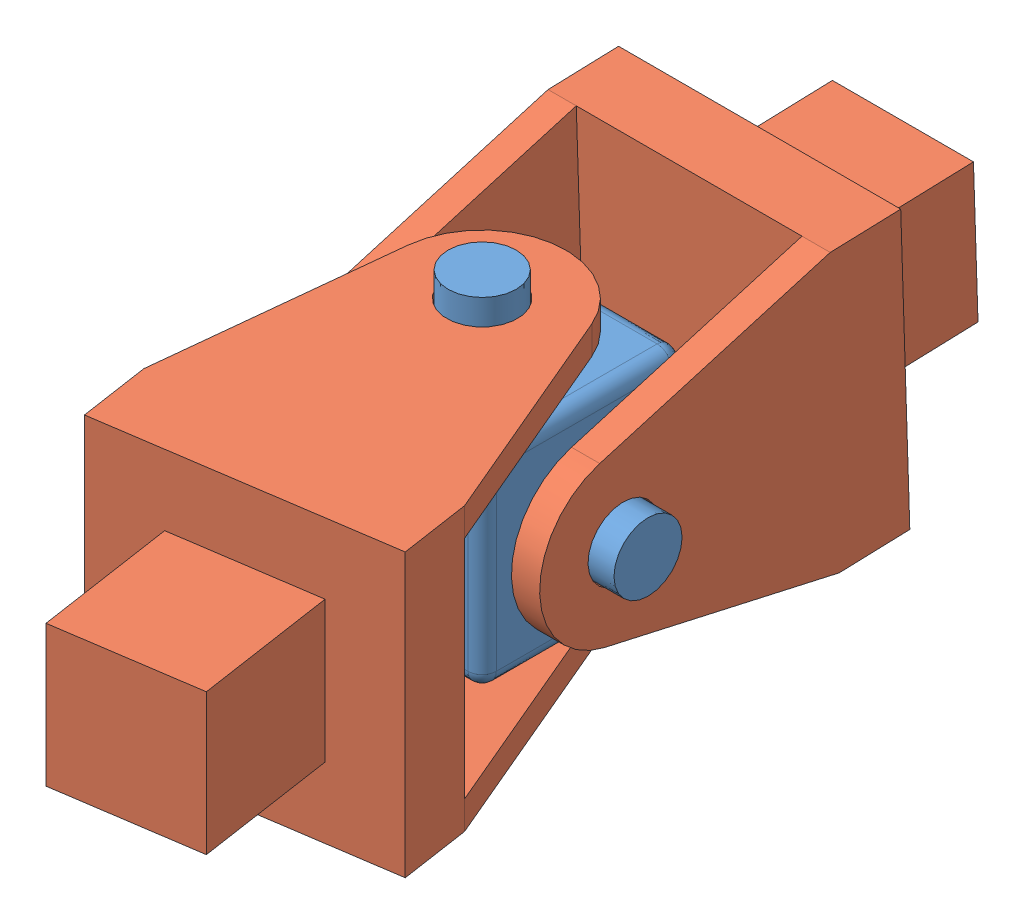
SolidWorks assembly U_assy, configuration Default. Lengths in mm.
Overall size (26.08 23.51 61.46).
3 component instances, 2 part files, 4 mates.
Components (placement in the parent):
- connector_new-2: connector_new [Default] at (0.0881 -0.2538 3.7177) size (23.51 23.51 14.4)
- U_leg-3: U_leg [Default] at (0.0881 0.3908 -16.2719) x (0 0.99948 0.032232) z (1 0 0) size (20 35.93 20)
- U_leg-4: U_leg [Default] at (3.0454 -0.2538 23.4979) x (0.989007 0 -0.147868) z (0 1 0) size (20 35.93 20)
Mates (geometry in assembly coordinates):
- Coincident3: coincident aligned: plane of connector_new-2 through (0.0881 -0.2538 3.7177) normal (1 0 0); plane of U_leg-3 through (0.0881 0.3908 -16.2719) normal (1 0 0)
- Concentric2: concentric anti-aligned: cylinder of connector_new-2 through (0.0881 11.5012 3.7177) axis (0 -1 0) radius 2.415; cylinder of U_leg-4 through (0.0881 -16.7538 3.7177) axis (0 1 0) radius 2.5
- Coincident4: coincident aligned: plane of connector_new-2 through (0.0881 -0.2538 3.7177) normal (0 1 0); plane of U_leg-4 through (3.0454 -0.2538 23.4979) normal (0 1 0)
- Concentric3: concentric anti-aligned: cylinder of connector_new-2 through (11.8431 -0.2538 3.7177) axis (-1 0 0) radius 2.415; cylinder of U_leg-3 through (-16.4119 -0.2538 3.7177) axis (1 0 0) radius 2.5
